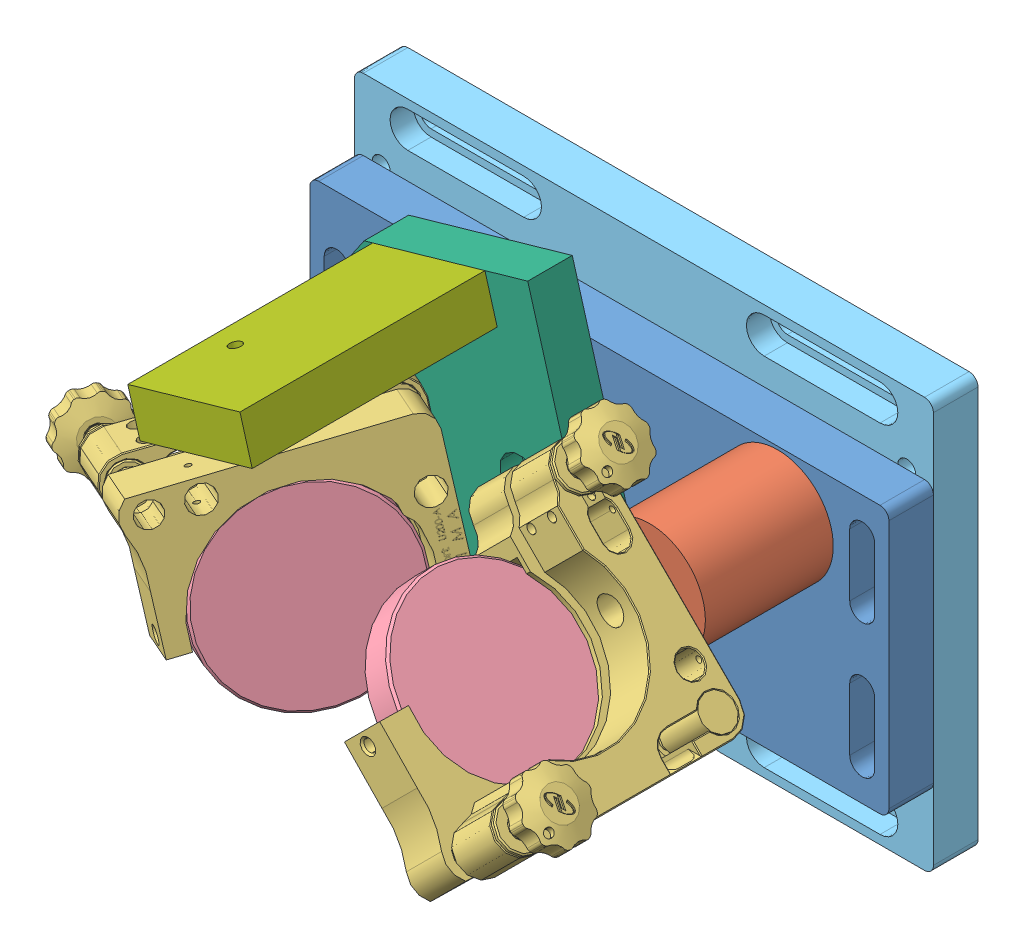
SolidWorks assembly D1101481_v3_ALS_X_End_Station_Upper_Periscope_Assemby, configuration Default. Lengths in mm.
Overall size (178.26 124.66 135).
12 component instances, 8 part files, 25 mates.
Components (placement in the parent):
- D1101868_v1_ALS_Upper_Periscope_Base-1: D1101868_v1_ALS_Upper_Periscope_Base [Default] at origin size (165.1 76.2 12.7)
- D1101871_v1_ALS_Upper_Periscope_Mirror_Post-1: D1101871_v1_ALS_Upper_Periscope_Mirror_Post [Default] at (50.8 21.336 12.7) x (1 0 0) z (0 -1 0) size (31.75 36.47 31.75)
- Newport U200 Mirror Mount Assembly-1: Newport U200 Mirror Mount Assembly [Default] at (66.5814 -10.1968 50.7459) x (-0.70706 0.70706 -0.011507) z (0.707107 0.707107 0) size (76.29 75.54 50.29)
  - U200-A2K-NL_Updated-1: U200-A2K-NL_Updated [Default] at origin size (76.29 75.54 50.29)
  - Precision Photonics_MI2045_2in_0475_Mirror-2: Precision Photonics_MI2045_2in_0475_Mirror [Default] at (33.401 33.401 -11.049) x (0.923728 0.383049 0) z (0 0 -1) size (50.8 50.8 9.53)
- D1101867_v1_ALS_Upper_Periscope_Baseplate-1: D1101867_v1_ALS_Upper_Periscope_Baseplate [Default] at (0 0 -12.7) x (1 0 0) z (0 -1 0) size (165.1 12.7 116.84)
- Periscope_Plate-1: Periscope_Plate [Default] at (-21.8363 -566.42 -12.7) (suppressed, hidden)
- D1101860_v1_ALS_Y_End_Lower_Periscope_Assembly-1: D1101860_v1_ALS_Y_End_Lower_Periscope_Assembly [Default] at (72.7162 -566.42 35.052) (suppressed, hidden)
- D1101869_v1_ALS_Upper_Periscope_Rotation_Base-1: D1101869_v1_ALS_Upper_Periscope_Rotation_Base [Default] at (15.7239 -25.8633 12.7) x (0.961262 0.275637 0) z (0 0 1) size (73.15 78.74 12.7)
- D1101870_v1_ALS_Upper_Periscope_Mirror_Base-1: D1101870_v1_ALS_Upper_Periscope_Mirror_Base [Default] at (-34.1803 41.7401 25.4) x (0.961262 0.275637 0) z (0 0 1) size (33.27 12.7 69.85)
- U200-A2K-NL_Updated-1: U200-A2K-NL_Updated [Default] at (-14.9058 39.1331 49.0812) x (0.28115 -0.959612 -0.009965) z (-0.832477 -0.238709 -0.5) size (76.29 75.54 50.29)
- Precision Photonics_MI2045_2in_0475_Mirror-1: Precision Photonics_MI2045_2in_0475_Mirror [Default] at (-12.2636 4.7461 83.197) x (0.500514 0.063042 -0.86343) z (0.832477 0.238709 0.5) size (50.8 50.8 9.53)
Mates (geometry in assembly coordinates):
- Coincident3: coincident anti-aligned: plane of D1101868_v1_ALS_Upper_Periscope_Base-1 through (82.55 -38.1 12.7) normal (0 0 1); plane of D1101871_v1_ALS_Upper_Periscope_Mirror_Post-1 through (50.8 21.336 12.7) normal (0 0 -1)
- Concentric2: concentric anti-aligned: cylinder of D1101868_v1_ALS_Upper_Periscope_Base-1 through (50.8 21.336 12.7) axis (0 0 1) radius 2.5527; cylinder of D1101871_v1_ALS_Upper_Periscope_Mirror_Post-1 through (50.8 21.336 12.7) axis (0 0 -1) radius 2.5527
- Coincident4: coincident anti-aligned: plane of D1101871_v1_ALS_Upper_Periscope_Mirror_Post-1 through (50.8 21.336 49.166) normal (0 0 1); plane of Newport U200 Mirror Mount Assembly-1/U200-A2K-NL_Updated-1 through (76.6182 6.7431 49.166) normal (0 0 -1)
- Concentric3: concentric aligned: cylinder of D1101871_v1_ALS_Upper_Periscope_Mirror_Post-1 through (50.8 21.336 49.166) axis (0 0 1) radius 1.7272; cylinder of Newport U200 Mirror Mount Assembly-1/U200-A2K-NL_Updated-1 through (50.8 21.336 60.5209) axis (0 0 1) radius 2.159
- Angle2: planar angle = 2.356194 rad aligned: plane of Newport U200 Mirror Mount Assembly-1/Precision Photonics_MI2045_2in_0475_Mirror-2 through (34.8803 5.8787 83.7603) normal (-0.707107 -0.707107 0); plane of D1101868_v1_ALS_Upper_Periscope_Base-1 through (-82.55 38.1 12.7) normal (0 1 0)
- Coincident5: coincident anti-aligned: plane of D1101868_v1_ALS_Upper_Periscope_Base-1 through (82.55 -38.1 0) normal (0 0 -1); plane of D1101867_v1_ALS_Upper_Periscope_Baseplate-1 through (82.55 -58.42 0) normal (0 0 1)
- Coincident6: coincident aligned: plane of D1101868_v1_ALS_Upper_Periscope_Base-1 through (82.55 38.1 12.7) normal (1 0 0); plane of D1101867_v1_ALS_Upper_Periscope_Baseplate-1 through (82.55 58.42 0) normal (1 0 0)
- Coincident7: coincident aligned: plane of D1101868_v1_ALS_Upper_Periscope_Base-1 through (0 0 0) normal (0 1 0); plane of D1101867_v1_ALS_Upper_Periscope_Baseplate-1
- Coincident8: coincident anti-aligned: plane of D1101867_v1_ALS_Upper_Periscope_Baseplate-1 through (82.55 -58.42 -12.7) normal (0 0 -1); plane of Periscope_Plate-1 through (-174.2363 -566.42 -12.7) normal (0 0 1)
- Parallel3: parallel aligned: plane of D1101867_v1_ALS_Upper_Periscope_Baseplate-1 through (-82.55 -58.42 0) normal (0 -1 0); plane of Periscope_Plate-1 through (-21.8363 -566.42 -38.1) normal (0 -1 0)
- Distance3: distance = 508 mm: line of D1101867_v1_ALS_Upper_Periscope_Baseplate-1 through (21.59 -58.42 -12.7) axis (1 0 0); line of Periscope_Plate-1 through (-174.2363 -566.42 -12.7) axis (1 0 0)
- Coincident9: coincident aligned: plane of Periscope_Plate-1 through (-21.8363 -566.42 -38.1) normal (0 -1 0); plane of D1101860_v1_ALS_Y_End_Lower_Periscope_Assembly-1 through (72.7162 -566.42 108.204) normal (0 -1 0)
- Distance4: distance = 47.752 mm anti-aligned: plane of D1101860_v1_ALS_Y_End_Lower_Periscope_Assembly-1 through (72.7162 -553.72 35.052) normal (0 0 -1); plane of Periscope_Plate-1 through (-174.2363 -566.42 -12.7) normal (0 0 1)
- Distance5: distance = 57.8474 mm aligned: plane of Periscope_Plate-1 through (130.5637 -566.42 -38.1) normal (1 0 0); plane of D1101860_v1_ALS_Y_End_Lower_Periscope_Assembly-1 through (72.7162 -553.72 35.052) normal (1 0 0)
- Coincident10: coincident anti-aligned: plane of D1101869_v1_ALS_Upper_Periscope_Rotation_Base-1 through (-7.7301 55.9304 25.4) normal (0 0 1); plane of D1101870_v1_ALS_Upper_Periscope_Mirror_Base-1 through (-48.4225 31.0503 25.4) normal (0 0 -1)
- Concentric4: concentric aligned: cylinder of D1101869_v1_ALS_Upper_Periscope_Rotation_Base-1 through (-42.7259 39.2896 12.7) axis (0 0 -1) radius 3.5712; cylinder of D1101870_v1_ALS_Upper_Periscope_Mirror_Base-1 through (-42.7259 39.2896 25.4) axis (0 0 -1) radius 2.5527
- Concentric5: concentric aligned: cylinder of D1101869_v1_ALS_Upper_Periscope_Rotation_Base-1 through (-25.6347 44.1905 12.7) axis (0 0 -1) radius 3.5712; cylinder of D1101870_v1_ALS_Upper_Periscope_Mirror_Base-1 through (-25.6347 44.1905 25.4) axis (0 0 -1) radius 2.5527
- Coincident11: coincident anti-aligned: plane of D1101870_v1_ALS_Upper_Periscope_Mirror_Base-1 through (-16.4375 40.2218 95.25) normal (0.275637 -0.961262 0); plane of U200-A2K-NL_Updated-1 through (-33.4832 35.3341 43.6746) normal (-0.275637 0.961262 0)
- Concentric6: concentric anti-aligned: cylinder of D1101870_v1_ALS_Upper_Periscope_Mirror_Base-1 through (-44.11 45.4987 72.39) axis (-0.275637 0.961262 0) radius 1.7272; cylinder of U200-A2K-NL_Updated-1 through (-37.4796 22.3756 72.39) axis (0.275637 -0.961262 0) radius 2.159
- Angle4: planar angle = 0.523599 rad aligned: plane of D1101870_v1_ALS_Upper_Periscope_Mirror_Base-1 through (-51.9231 43.2583 95.25) normal (-0.961262 -0.275637 0); plane of U200-A2K-NL_Updated-1 through (-15.9802 -25.7061 43.6746) normal (-0.832477 -0.238709 -0.5)
- Coincident15: coincident anti-aligned: plane of U200-A2K-NL_Updated-1 through (-20.193 2.4724 78.4345) normal (0.832477 0.238709 0.5); plane of Precision Photonics_MI2045_2in_0475_Mirror-1 through (-20.193 2.4724 78.4345) normal (-0.832477 -0.238709 -0.5)
- Concentric7: concentric aligned: cylinder of U200-A2K-NL_Updated-1 through (-9.6205 5.504 84.7845) axis (0.832477 0.238709 0.5) radius 26.416; cylinder of Precision Photonics_MI2045_2in_0475_Mirror-1 through (-20.193 2.4724 78.4345) axis (0.832477 0.238709 0.5) radius 25.4
- Coincident16: coincident anti-aligned: plane of D1101868_v1_ALS_Upper_Periscope_Base-1 through (82.55 -38.1 12.7) normal (0 0 1); plane of D1101869_v1_ALS_Upper_Periscope_Rotation_Base-1 through (-7.7301 55.9304 12.7) normal (0 0 -1)
- Concentric8: concentric aligned: cylinder of D1101868_v1_ALS_Upper_Periscope_Base-1 through (-10.16 6.35 12.7) axis (0 0 1) radius 2.5527; cylinder of D1101869_v1_ALS_Upper_Periscope_Rotation_Base-1 through (-10.16 6.35 25.4) axis (0 0 1) radius 3.5712
- Angle5: planar angle = 0.279253 rad aligned: plane of D1101869_v1_ALS_Upper_Periscope_Rotation_Base-1 through (-7.7301 55.9304 25.4) normal (-0.275637 0.961262 0); plane of D1101868_v1_ALS_Upper_Periscope_Base-1 through (-82.55 38.1 12.7) normal (0 1 0)
